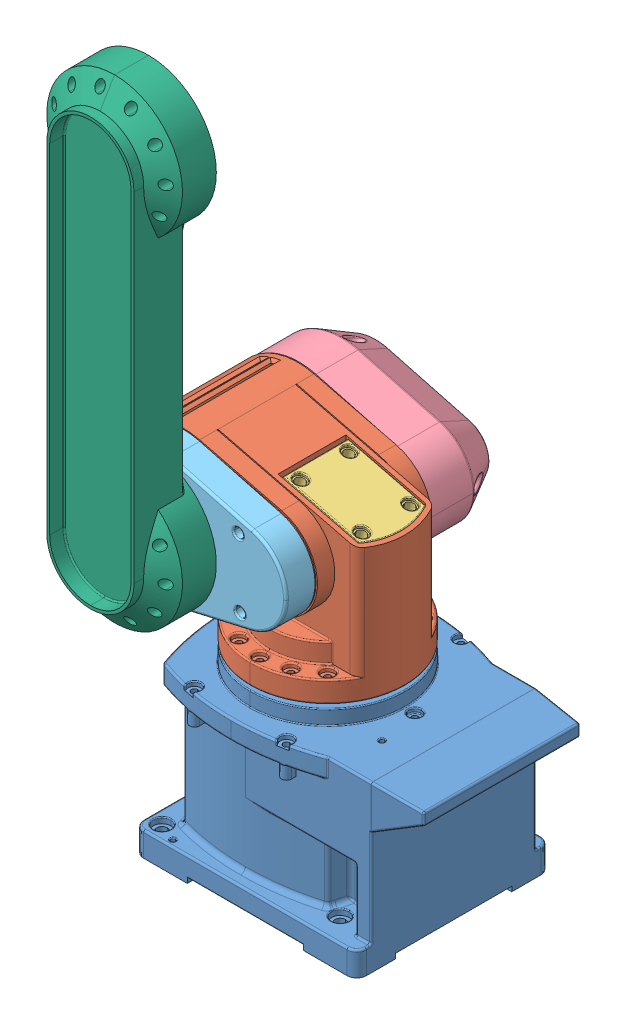
SolidWorks assembly movable step 1, configuration Default. Lengths in mm.
Overall size (340.1 715.79 303.13).
6 component instances, 6 part files, 15 mates.
Components (placement in the parent):
- Base.step-1: Base.step [Default] at (50.4601 21.8888 234.5287) size (280 185 200)
- Joint_1.step-1: Joint_1.step [Default] at (68.2167 333.4398 234.5287) size (242.75 189 160)
- Joint_1_top_cap.step-1: Joint_1_top_cap.step [Default] at (70.5148 316.8888 234.5287) x (1 0 0) z (0 1 0) size (91.2 70 52.34)
- Part3.step-1: Part3.step [Default] at (63.4179 21.928 234.5287) x (0.999815 -0.016322 -0.010154) z (0.010153 -0.000166 0.999948) size (205.53 137 83.39)
- Part4.step-1: Part4.step [Default] at (63.4179 21.928 234.5287) x (0.999815 -0.016322 -0.010154) z (0.010153 -0.000166 0.999948) size (205.37 137 45.97)
- Joint_2.step-1: Joint_2.step [Default] at (-21.7667 647.378 238.6434) x (0 -0.999953 -0.009698) z (0.003009 -0.009698 0.999948) size (490.3 140.11 64.56)
Mates (geometry in assembly coordinates):
- Concentric1: concentric aligned: cylinder of Base.step-1 through (68.2167 206.8888 234.5287) axis (0 -1 0) radius 80; cylinder of Joint_1.step-1 through (68.2167 222.8888 234.5287) axis (0 -1 0) radius 69
- Coincident1: coincident anti-aligned: plane of Base.step-1 through (68.2167 196.8888 234.5287) normal (0 1 0); plane of Joint_1.step-1 through (68.2167 196.8888 234.5287) normal (0 -1 0)
- Parallel1: parallel aligned: plane of Base.step-1 through (198.2167 111.8888 319.5287) normal (0 0 1); plane of Joint_1.step-1 through (68.2167 333.4398 274.5287) normal (0 0 1)
- Coincident2: coincident anti-aligned: plane of Joint_1.step-1 through (68.2167 316.8888 234.5287) normal (0 1 0); plane of Joint_1_top_cap.step-1 through (70.5148 316.8888 234.5287) normal (0 -1 0)
- Concentric3: concentric aligned: cylinder of Joint_1.step-1 through (68.2167 385.8888 234.5287) axis (0 -1 0) radius 75; cylinder of Joint_1_top_cap.step-1 through (68.2167 470.6805 234.5287) axis (0 -1 0) radius 75.4393
- Parallel2: parallel anti-aligned: plane of Joint_1.step-1 through (52.0118 385.8888 269.5287) normal (1 0 0); plane of Joint_1_top_cap.step-1 through (55.8099 470.6805 201.0287) normal (-1 0 0)
- Coincident3: coincident anti-aligned: plane of Joint_1.step-1 through (68.2167 333.4398 174.5287) normal (0 0 -1); plane of Part3.step-1 through (68.2167 315.8888 174.5287) normal (0 0 1)
- Concentric4: concentric anti-aligned: cylinder of Joint_1.step-1 through (68.2167 315.8888 274.5287) axis (0 0 -1) radius 48.4134; cylinder of Part3.step-1 through (68.2167 315.8888 94.5287) axis (0 0 1) radius 46.9225
- Tangent1: tangent aligned: cylinder of Joint_1.step-1 through (-21.7787 315.8888 274.5287) axis (0 0 -1) radius 70; cylinder of Part3.step-1 through (-21.4511 317.3526 94.5287) axis (0 0 1) radius 68.5
- Coincident4: coincident anti-aligned: plane of Joint_1.step-1 through (68.2167 333.4398 294.5287) normal (0 0 1); plane of Part4.step-1 through (68.2167 315.8888 294.5287) normal (0 0 -1)
- Concentric6: concentric aligned: cylinder of Joint_1.step-1 through (68.2167 315.8888 274.5287) axis (0 0 -1) radius 48.4134; cylinder of Part4.step-1 through (68.2167 315.8888 324.5287) axis (0 0 -1) radius 46.9225
- Tangent2: tangent aligned: cylinder of Joint_1.step-1 through (-21.7787 315.8888 274.5287) axis (0 0 -1) radius 70; cylinder of Part4.step-1 through (-21.4511 317.3526 324.5287) axis (0 0 -1) radius 68.5
- Coincident5: coincident: plane of Part4.step-1 through (-21.7667 317.3577 329.5287) normal (0 0 1); plane of Joint_2.step-1 through (-21.7667 44.306 161.1741) normal (0 0 -1)
- Concentric7: concentric: cylinder of Part4.step-1 through (-21.7667 317.3577 339.5287) axis (0 0 -1) radius 30; cylinder of Joint_2.step-1 through (-21.7667 44.306 171.1741) axis (0 0 -1) radius 30
- Parallel3: parallel aligned: plane of Base.step-1 through (198.2167 46.8888 134.5287) normal (1 0 0); plane of Joint_2.step-1
